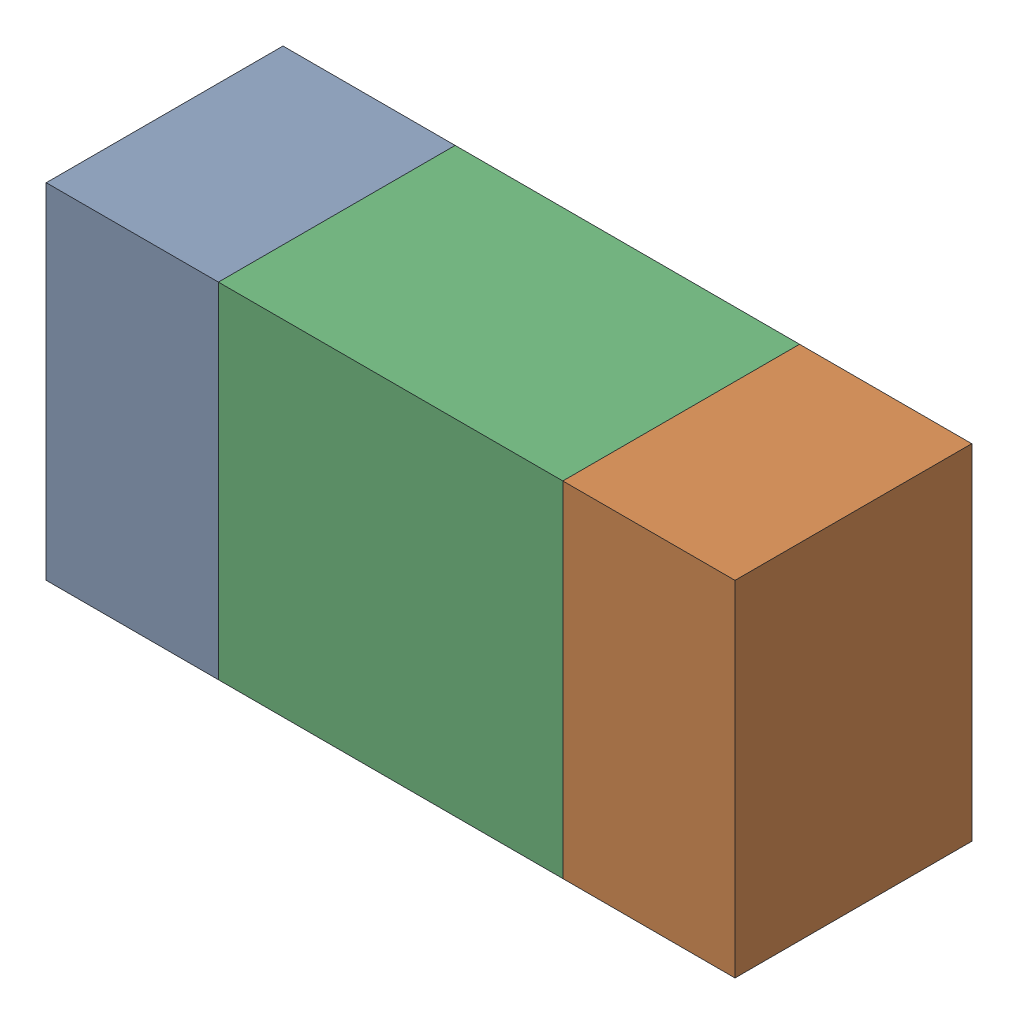
SolidWorks assembly R11, configuration ﾃﾞﾌｫﾙﾄ. Lengths in mm.
Overall size (1.6 0.8 0.55).
6 component instances, 2 part files, 0 mates.
Components (placement in the parent):
- 689261512-1: 689261512 [ﾃﾞﾌｫﾙﾄ] at (6.4001 31.2501 0) size (0.4 0.8 0.55)
  - Extruded_32-1: Extruded_32 [ﾃﾞﾌｫﾙﾄ] at origin size (0.4 0.8 0.55)
- 689261512-2: 689261512 [ﾃﾞﾌｫﾙﾄ] at (7.6001 31.2501 0) size (0.4 0.8 0.55)
  - Extruded_32-1: Extruded_32 [ﾃﾞﾌｫﾙﾄ] at origin size (0.4 0.8 0.55)
- 689261648-1: 689261648 [ﾃﾞﾌｫﾙﾄ] at (7 31.2501 0) size (0.8 0.8 0.55)
  - Extruded_33-1: Extruded_33 [ﾃﾞﾌｫﾙﾄ] at origin size (0.8 0.8 0.55)
